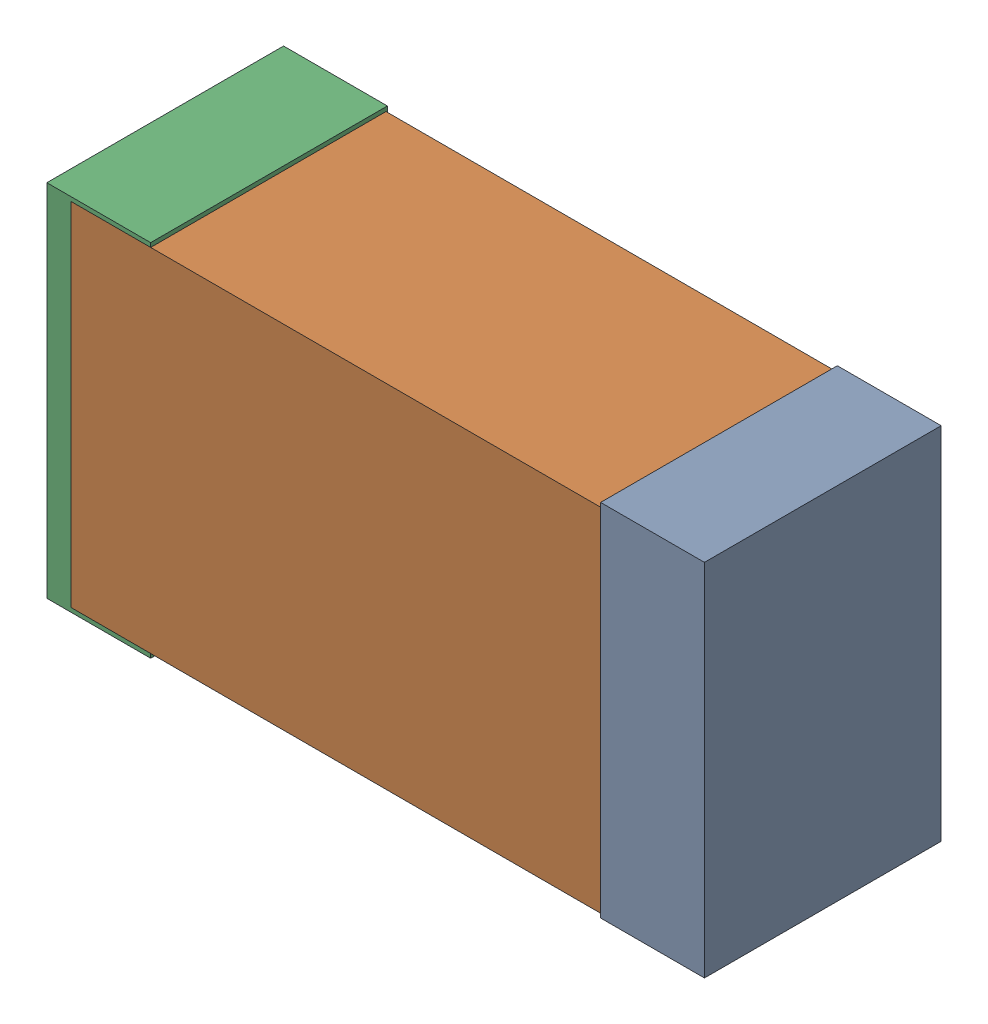
SolidWorks assembly USB23_C8, configuration Default. Lengths in mm.
Overall size (2.38 1.3 0.85).
6 component instances, 2 part files, 0 mates.
Components (placement in the parent):
- 384311232-1: 384311232 [Default] at (157.718 59.182 -1.9574) size (0.38 1.3 0.85)
  - Extruded_8-1: Extruded_8 [Default] at origin size (0.38 1.3 0.85)
- 402662800-1: 402662800 [Default] at (156.718 59.182 -1.9524) size (2.2 1.27 0.85)
  - Extruded_30-1: Extruded_30 [Default] at origin size (2.2 1.27 0.85)
- 384311232-2: 384311232 [Default] at (155.718 59.182 -1.9574) size (0.38 1.3 0.85)
  - Extruded_8-1: Extruded_8 [Default] at origin size (0.38 1.3 0.85)
